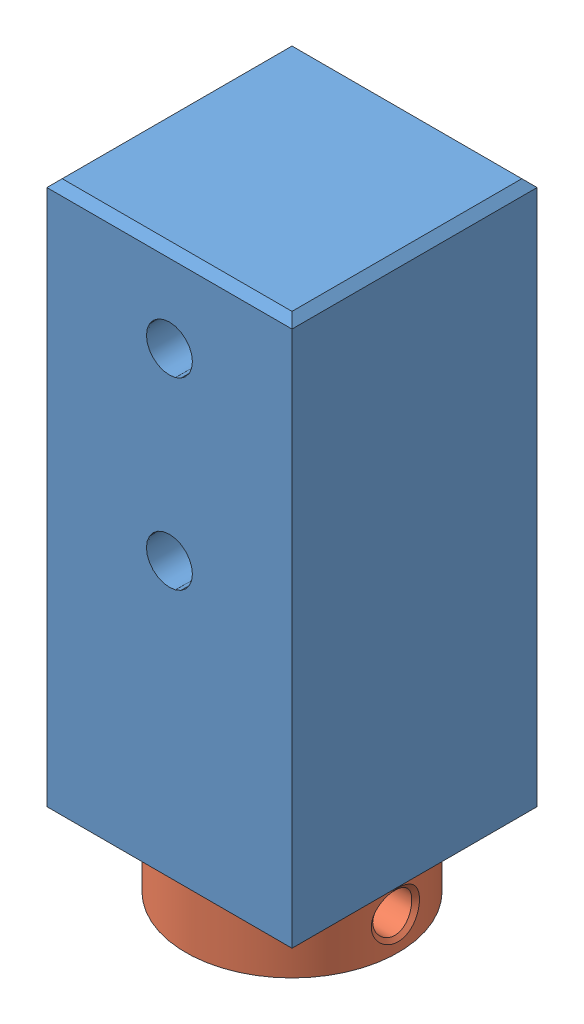
SolidWorks assembly Agitator NeveRest Motor Mount, configuration Default. Lengths in mm.
Overall size (31.11 66.75 31.11).
2 component instances, 2 part files, 3 mates.
Components (placement in the parent):
- Agitator NeveRest Motor Mount-1: Agitator NeveRest Motor Mount [Default] at (4.3224 33.4035 50.4117) size (25.4 57.15 25.4)
- Motor Shaft Hub-1: Motor Shaft Hub [Default] at (4.3224 1.4285 50.4117) x (0.707107 0 -0.707107) z (0 -1 0) size (22 22 9.6)
Mates (geometry in assembly coordinates):
- Concentric1: concentric aligned: cylinder of Agitator NeveRest Motor Mount-1 through (4.3224 23.8785 50.4117) axis (0 -1 0) radius 3.175; cylinder of Motor Shaft Hub-1 through (4.3224 4.8285 50.4117) axis (0 -1 0) radius 3
- Coincident1: coincident anti-aligned: plane of Agitator NeveRest Motor Mount-1 through (4.3224 4.8285 50.4117) normal (0 -1 0); plane of Motor Shaft Hub-1 through (4.3224 4.8285 50.4117) normal (0 1 0)
- Angle1: planar angle = 0.785398 rad aligned: plane of Motor Shaft Hub-1; plane of assembly through (0 0 0) normal (1 0 0)
